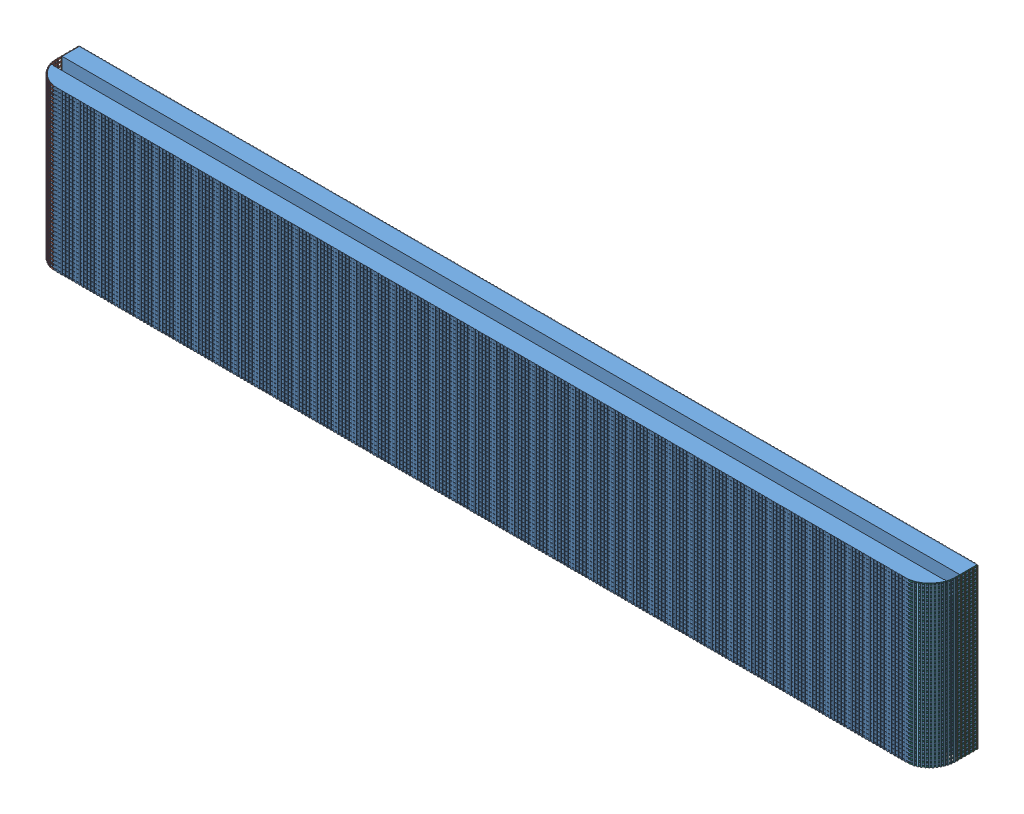
SolidWorks assembly B_neo_texture_part1, configuration Default. Lengths in mm.
Overall size (450.81 79.89 24).
123 component instances, 6 part files, 20 mates.
Components (placement in the parent):
- B_neo_part1-1: B_neo_part1 [Default] at (-250.0255 -30.6599 18.4974) size (450 79.89 24)
- Part5^B_neo_texture_part1-1: Part5^B_neo_texture_part1 [Default] at (-250.0255 49.2301 18.4974) x (1 0 0) z (0 1 0) size (10.93 23.6 0.6) (virtual)
- Part5^B_neo_texture_part1-2: Part5^B_neo_texture_part1 [Default] at (-250.0255 47.4301 18.4974) x (1 0 0) z (0 1 0) size (10.93 23.6 0.6) (virtual)
- Part5^B_neo_texture_part1-3: Part5^B_neo_texture_part1 [Default] at (-250.0255 45.6301 18.4974) x (1 0 0) z (0 1 0) size (10.93 23.6 0.6) (virtual)
- Part5^B_neo_texture_part1-4: Part5^B_neo_texture_part1 [Default] at (-250.0255 43.8301 18.4974) x (1 0 0) z (0 1 0) size (10.93 23.6 0.6) (virtual)
- Part5^B_neo_texture_part1-5: Part5^B_neo_texture_part1 [Default] at (-250.0255 42.0301 18.4974) x (1 0 0) z (0 1 0) size (10.93 23.6 0.6) (virtual)
- Part5^B_neo_texture_part1-6: Part5^B_neo_texture_part1 [Default] at (-250.0255 40.2301 18.4974) x (1 0 0) z (0 1 0) size (10.93 23.6 0.6) (virtual)
- Part5^B_neo_texture_part1-7: Part5^B_neo_texture_part1 [Default] at (-250.0255 38.4301 18.4974) x (1 0 0) z (0 1 0) size (10.93 23.6 0.6) (virtual)
- Part5^B_neo_texture_part1-8: Part5^B_neo_texture_part1 [Default] at (-250.0255 36.6301 18.4974) x (1 0 0) z (0 1 0) size (10.93 23.6 0.6) (virtual)
- Part5^B_neo_texture_part1-9: Part5^B_neo_texture_part1 [Default] at (-250.0255 34.8301 18.4974) x (1 0 0) z (0 1 0) size (10.93 23.6 0.6) (virtual)
- Part5^B_neo_texture_part1-10: Part5^B_neo_texture_part1 [Default] at (-250.0255 33.0301 18.4974) x (1 0 0) z (0 1 0) size (10.93 23.6 0.6) (virtual)
- Part5^B_neo_texture_part1-11: Part5^B_neo_texture_part1 [Default] at (-250.0255 31.2301 18.4974) x (1 0 0) z (0 1 0) size (10.93 23.6 0.6) (virtual)
- Part5^B_neo_texture_part1-12: Part5^B_neo_texture_part1 [Default] at (-250.0255 29.4301 18.4974) x (1 0 0) z (0 1 0) size (10.93 23.6 0.6) (virtual)
- Part5^B_neo_texture_part1-13: Part5^B_neo_texture_part1 [Default] at (-250.0255 27.6301 18.4974) x (1 0 0) z (0 1 0) size (10.93 23.6 0.6) (virtual)
- Part5^B_neo_texture_part1-14: Part5^B_neo_texture_part1 [Default] at (-250.0255 25.8301 18.4974) x (1 0 0) z (0 1 0) size (10.93 23.6 0.6) (virtual)
- Part5^B_neo_texture_part1-15: Part5^B_neo_texture_part1 [Default] at (-250.0255 24.0301 18.4974) x (1 0 0) z (0 1 0) size (10.93 23.6 0.6) (virtual)
- Part5^B_neo_texture_part1-16: Part5^B_neo_texture_part1 [Default] at (-250.0255 22.2301 18.4974) x (1 0 0) z (0 1 0) size (10.93 23.6 0.6) (virtual)
- Part5^B_neo_texture_part1-17: Part5^B_neo_texture_part1 [Default] at (-250.0255 20.4301 18.4974) x (1 0 0) z (0 1 0) size (10.93 23.6 0.6) (virtual)
- Part5^B_neo_texture_part1-18: Part5^B_neo_texture_part1 [Default] at (-250.0255 18.6301 18.4974) x (1 0 0) z (0 1 0) size (10.93 23.6 0.6) (virtual)
- Part5^B_neo_texture_part1-19: Part5^B_neo_texture_part1 [Default] at (-250.0255 16.8301 18.4974) x (1 0 0) z (0 1 0) size (10.93 23.6 0.6) (virtual)
- Part5^B_neo_texture_part1-20: Part5^B_neo_texture_part1 [Default] at (-250.0255 15.0301 18.4974) x (1 0 0) z (0 1 0) size (10.93 23.6 0.6) (virtual)
- Part5^B_neo_texture_part1-21: Part5^B_neo_texture_part1 [Default] at (-250.0255 13.2301 18.4974) x (1 0 0) z (0 1 0) size (10.93 23.6 0.6) (virtual)
- Part5^B_neo_texture_part1-22: Part5^B_neo_texture_part1 [Default] at (-250.0255 11.4301 18.4974) x (1 0 0) z (0 1 0) size (10.93 23.6 0.6) (virtual)
- Part5^B_neo_texture_part1-23: Part5^B_neo_texture_part1 [Default] at (-250.0255 9.6301 18.4974) x (1 0 0) z (0 1 0) size (10.93 23.6 0.6) (virtual)
- Part5^B_neo_texture_part1-24: Part5^B_neo_texture_part1 [Default] at (-250.0255 7.8301 18.4974) x (1 0 0) z (0 1 0) size (10.93 23.6 0.6) (virtual)
- Part5^B_neo_texture_part1-25: Part5^B_neo_texture_part1 [Default] at (-250.0255 6.0301 18.4974) x (1 0 0) z (0 1 0) size (10.93 23.6 0.6) (virtual)
- Part5^B_neo_texture_part1-26: Part5^B_neo_texture_part1 [Default] at (-250.0255 4.2301 18.4974) x (1 0 0) z (0 1 0) size (10.93 23.6 0.6) (virtual)
- Part5^B_neo_texture_part1-27: Part5^B_neo_texture_part1 [Default] at (-250.0255 2.4301 18.4974) x (1 0 0) z (0 1 0) size (10.93 23.6 0.6) (virtual)
- Part5^B_neo_texture_part1-28: Part5^B_neo_texture_part1 [Default] at (-250.0255 0.6301 18.4974) x (1 0 0) z (0 1 0) size (10.93 23.6 0.6) (virtual)
- Part5^B_neo_texture_part1-29: Part5^B_neo_texture_part1 [Default] at (-250.0255 -1.1699 18.4974) x (1 0 0) z (0 1 0) size (10.93 23.6 0.6) (virtual)
- Part5^B_neo_texture_part1-30: Part5^B_neo_texture_part1 [Default] at (-250.0255 -2.9699 18.4974) x (1 0 0) z (0 1 0) size (10.93 23.6 0.6) (virtual)
- Part5^B_neo_texture_part1-31: Part5^B_neo_texture_part1 [Default] at (-250.0255 -4.7699 18.4974) x (1 0 0) z (0 1 0) size (10.93 23.6 0.6) (virtual)
- Part5^B_neo_texture_part1-32: Part5^B_neo_texture_part1 [Default] at (-250.0255 -6.5699 18.4974) x (1 0 0) z (0 1 0) size (10.93 23.6 0.6) (virtual)
- Part5^B_neo_texture_part1-33: Part5^B_neo_texture_part1 [Default] at (-250.0255 -8.3699 18.4974) x (1 0 0) z (0 1 0) size (10.93 23.6 0.6) (virtual)
- Part5^B_neo_texture_part1-34: Part5^B_neo_texture_part1 [Default] at (-250.0255 -10.1699 18.4974) x (1 0 0) z (0 1 0) size (10.93 23.6 0.6) (virtual)
- Part5^B_neo_texture_part1-35: Part5^B_neo_texture_part1 [Default] at (-250.0255 -11.9699 18.4974) x (1 0 0) z (0 1 0) size (10.93 23.6 0.6) (virtual)
- Part5^B_neo_texture_part1-36: Part5^B_neo_texture_part1 [Default] at (-250.0255 -13.7699 18.4974) x (1 0 0) z (0 1 0) size (10.93 23.6 0.6) (virtual)
- Part5^B_neo_texture_part1-37: Part5^B_neo_texture_part1 [Default] at (-250.0255 -15.5699 18.4974) x (1 0 0) z (0 1 0) size (10.93 23.6 0.6) (virtual)
- Part5^B_neo_texture_part1-38: Part5^B_neo_texture_part1 [Default] at (-250.0255 -17.3699 18.4974) x (1 0 0) z (0 1 0) size (10.93 23.6 0.6) (virtual)
- Part5^B_neo_texture_part1-39: Part5^B_neo_texture_part1 [Default] at (-250.0255 -19.1699 18.4974) x (1 0 0) z (0 1 0) size (10.93 23.6 0.6) (virtual)
- Part5^B_neo_texture_part1-40: Part5^B_neo_texture_part1 [Default] at (-250.0255 -20.9699 18.4974) x (1 0 0) z (0 1 0) size (10.93 23.6 0.6) (virtual)
- Part5^B_neo_texture_part1-41: Part5^B_neo_texture_part1 [Default] at (-250.0255 -22.7699 18.4974) x (1 0 0) z (0 1 0) size (10.93 23.6 0.6) (virtual)
- Part5^B_neo_texture_part1-42: Part5^B_neo_texture_part1 [Default] at (-250.0255 -24.5699 18.4974) x (1 0 0) z (0 1 0) size (10.93 23.6 0.6) (virtual)
- Part5^B_neo_texture_part1-43: Part5^B_neo_texture_part1 [Default] at (-250.0255 -26.3699 18.4974) x (1 0 0) z (0 1 0) size (10.93 23.6 0.6) (virtual)
- Part5^B_neo_texture_part1-44: Part5^B_neo_texture_part1 [Default] at (-250.0255 -28.1699 18.4974) x (1 0 0) z (0 1 0) size (10.93 23.6 0.6) (virtual)
- Part5^B_neo_texture_part1-45: Part5^B_neo_texture_part1 [Default] at (-250.0255 -29.9699 18.4974) x (1 0 0) z (0 1 0) size (10.93 23.6 0.6) (virtual)
- Part6^B_neo_texture_part1-1: Part6^B_neo_texture_part1 [Default] at (-250.0255 49.2301 18.4974) x (1 0 0) z (0 1 0) size (450.8 0.81 79.89) (virtual)
- Part6^B_neo_texture_part1-2: Part6^B_neo_texture_part1 [Default] at (-250.0255 49.2301 20.4974) x (1 0 0) z (0 1 0) size (450.8 0.81 79.89) (virtual)
- Part6^B_neo_texture_part1-3: Part6^B_neo_texture_part1 [Default] at (-250.0255 49.2301 22.4974) x (1 0 0) z (0 1 0) size (450.8 0.81 79.89) (virtual)
- Part6^B_neo_texture_part1-4: Part6^B_neo_texture_part1 [Default] at (-250.0255 49.2301 24.4974) x (1 0 0) z (0 1 0) size (450.8 0.81 79.89) (virtual)
- Part6^B_neo_texture_part1-5: Part6^B_neo_texture_part1 [Default] at (-250.0255 49.2301 26.4974) x (1 0 0) z (0 1 0) size (450.8 0.81 79.89) (virtual)
- Part6^B_neo_texture_part1-6: Part6^B_neo_texture_part1 [Default] at (-250.0255 49.2301 28.4974) x (1 0 0) z (0 1 0) size (450.8 0.81 79.89) (virtual)
- Part7^B_neo_texture_part1-1: Part7^B_neo_texture_part1 [Default] at (-250.0255 49.2301 28.4974) x (1 0 0) z (0 1 0) size (0.2 0.6 79.89) (virtual)
- Part7^B_neo_texture_part1-2: Part7^B_neo_texture_part1 [Default] at (-247.592 49.2301 29.7325) x (0.994522 0 -0.104528) z (0 1 0) size (0.2 0.6 79.89) (virtual)
- Part7^B_neo_texture_part1-3: Part7^B_neo_texture_part1 [Default] at (-245.0427 49.2301 30.7064) x (0.978148 0 -0.207912) z (0 1 0) size (0.2 0.6 79.89) (virtual)
- Part7^B_neo_texture_part1-4: Part7^B_neo_texture_part1 [Default] at (-242.4055 49.2301 31.4085) x (0.951057 0 -0.309017) z (0 1 0) size (0.2 0.6 79.89) (virtual)
- Part7^B_neo_texture_part1-5: Part7^B_neo_texture_part1 [Default] at (-239.7094 49.2301 31.8312) x (0.913545 0 -0.406737) z (0 1 0) size (0.2 0.6 79.89) (virtual)
- Part7^B_neo_texture_part1-6: Part7^B_neo_texture_part1 [Default] at (-236.9839 49.2301 31.9696) x (0.866025 0 -0.5) z (0 1 0) size (0.2 0.6 79.89) (virtual)
- Part7^B_neo_texture_part1-7: Part7^B_neo_texture_part1 [Default] at (-234.2588 49.2301 31.8224) x (0.809017 0 -0.587785) z (0 1 0) size (0.2 0.6 79.89) (virtual)
- Part7^B_neo_texture_part1-8: Part7^B_neo_texture_part1 [Default] at (-231.5641 49.2301 31.3912) x (0.743145 0 -0.669131) z (0 1 0) size (0.2 0.6 79.89) (virtual)
- Part7^B_neo_texture_part1-9: Part7^B_neo_texture_part1 [Default] at (-228.9292 49.2301 30.6807) x (0.669131 0 -0.743145) z (0 1 0) size (0.2 0.6 79.89) (virtual)
- Part7^B_neo_texture_part1-10: Part7^B_neo_texture_part1 [Default] at (-226.383 49.2301 29.6986) x (0.587785 0 -0.809017) z (0 1 0) size (0.2 0.6 79.89) (virtual)
- Part7^B_neo_texture_part1-11: Part7^B_neo_texture_part1 [Default] at (-223.9534 49.2301 28.4558) x (0.5 0 -0.866025) z (0 1 0) size (0.2 0.6 79.89) (virtual)
- Part7^B_neo_texture_part1-12: Part7^B_neo_texture_part1 [Default] at (-221.667 49.2301 26.9658) x (0.406737 0 -0.913545) z (0 1 0) size (0.2 0.6 79.89) (virtual)
- Part7^B_neo_texture_part1-13: Part7^B_neo_texture_part1 [Default] at (-219.5489 49.2301 25.245) x (0.309017 0 -0.951057) z (0 1 0) size (0.2 0.6 79.89) (virtual)
- Part8^B_neo_texture_part1-1: Part8^B_neo_texture_part1 [Default] at (-250.0255 49.2301 28.4974) x (1 0 0) z (0 1 0) size (0.2 0.6 79.89) (virtual)
- Part8^B_neo_texture_part1-2: Part8^B_neo_texture_part1 [Default] at (-249.9939 49.2301 -17.3053) x (0.994522 0 0.104528) z (0 1 0) size (0.2 0.6 79.89) (virtual)
- Part8^B_neo_texture_part1-3: Part8^B_neo_texture_part1 [Default] at (-245.1748 49.2301 -62.8538) x (0.978148 0 0.207912) z (0 1 0) size (0.2 0.6 79.89) (virtual)
- Part8^B_neo_texture_part1-4: Part8^B_neo_texture_part1 [Default] at (-235.621 49.2301 -107.6491) x (0.951057 0 0.309017) z (0 1 0) size (0.2 0.6 79.89) (virtual)
- Part8^B_neo_texture_part1-5: Part8^B_neo_texture_part1 [Default] at (-221.4372 49.2301 -151.2003) x (0.913545 0 0.406737) z (0 1 0) size (0.2 0.6 79.89) (virtual)
- Part8^B_neo_texture_part1-6: Part8^B_neo_texture_part1 [Default] at (-202.7786 49.2301 -193.0304) x (0.866025 0 0.5) z (0 1 0) size (0.2 0.6 79.89) (virtual)
- Part8^B_neo_texture_part1-7: Part8^B_neo_texture_part1 [Default] at (-179.8499 49.2301 -232.6809) x (0.809017 0 0.587785) z (0 1 0) size (0.2 0.6 79.89) (virtual)
- Part8^B_neo_texture_part1-8: Part8^B_neo_texture_part1 [Default] at (-152.9022 49.2301 -269.7176) x (0.743145 0 0.669131) z (0 1 0) size (0.2 0.6 79.89) (virtual)
- Part8^B_neo_texture_part1-9: Part8^B_neo_texture_part1 [Default] at (-122.2307 49.2301 -303.7345) x (0.669131 0 0.743145) z (0 1 0) size (0.2 0.6 79.89) (virtual)
- Part8^B_neo_texture_part1-10: Part8^B_neo_texture_part1 [Default] at (-88.1715 49.2301 -334.359) x (0.587785 0 0.809017) z (0 1 0) size (0.2 0.6 79.89) (virtual)
- Part8^B_neo_texture_part1-11: Part8^B_neo_texture_part1 [Default] at (-51.0977 49.2301 -361.2557) x (0.5 0 0.866025) z (0 1 0) size (0.2 0.6 79.89) (virtual)
- Part8^B_neo_texture_part1-12: Part8^B_neo_texture_part1 [Default] at (-11.4156 49.2301 -384.1297) x (0.406737 0 0.913545) z (0 1 0) size (0.2 0.6 79.89) (virtual)
- Part8^B_neo_texture_part1-13: Part8^B_neo_texture_part1 [Default] at (30.4402 49.2301 -402.7305) x (0.309017 0 0.951057) z (0 1 0) size (0.2 0.6 79.89) (virtual)
- Part10^B_neo_texture_part1-1: Part10^B_neo_texture_part1 [Default] at (-250.0255 49.2301 18.4974) x (1 0 0) z (0 1 0) size (10.93 23.6 0.6) (virtual)
- Part10^B_neo_texture_part1-2: Part10^B_neo_texture_part1 [Default] at (-250.0255 47.4301 18.4974) x (1 0 0) z (0 1 0) size (10.93 23.6 0.6) (virtual)
- Part10^B_neo_texture_part1-3: Part10^B_neo_texture_part1 [Default] at (-250.0255 45.6301 18.4974) x (1 0 0) z (0 1 0) size (10.93 23.6 0.6) (virtual)
- Part10^B_neo_texture_part1-4: Part10^B_neo_texture_part1 [Default] at (-250.0255 43.8301 18.4974) x (1 0 0) z (0 1 0) size (10.93 23.6 0.6) (virtual)
- Part10^B_neo_texture_part1-5: Part10^B_neo_texture_part1 [Default] at (-250.0255 42.0301 18.4974) x (1 0 0) z (0 1 0) size (10.93 23.6 0.6) (virtual)
- Part10^B_neo_texture_part1-6: Part10^B_neo_texture_part1 [Default] at (-250.0255 40.2301 18.4974) x (1 0 0) z (0 1 0) size (10.93 23.6 0.6) (virtual)
- Part10^B_neo_texture_part1-7: Part10^B_neo_texture_part1 [Default] at (-250.0255 38.4301 18.4974) x (1 0 0) z (0 1 0) size (10.93 23.6 0.6) (virtual)
- Part10^B_neo_texture_part1-8: Part10^B_neo_texture_part1 [Default] at (-250.0255 36.6301 18.4974) x (1 0 0) z (0 1 0) size (10.93 23.6 0.6) (virtual)
- Part10^B_neo_texture_part1-9: Part10^B_neo_texture_part1 [Default] at (-250.0255 34.8301 18.4974) x (1 0 0) z (0 1 0) size (10.93 23.6 0.6) (virtual)
- Part10^B_neo_texture_part1-10: Part10^B_neo_texture_part1 [Default] at (-250.0255 33.0301 18.4974) x (1 0 0) z (0 1 0) size (10.93 23.6 0.6) (virtual)
- Part10^B_neo_texture_part1-11: Part10^B_neo_texture_part1 [Default] at (-250.0255 31.2301 18.4974) x (1 0 0) z (0 1 0) size (10.93 23.6 0.6) (virtual)
- Part10^B_neo_texture_part1-12: Part10^B_neo_texture_part1 [Default] at (-250.0255 29.4301 18.4974) x (1 0 0) z (0 1 0) size (10.93 23.6 0.6) (virtual)
- Part10^B_neo_texture_part1-13: Part10^B_neo_texture_part1 [Default] at (-250.0255 27.6301 18.4974) x (1 0 0) z (0 1 0) size (10.93 23.6 0.6) (virtual)
- Part10^B_neo_texture_part1-14: Part10^B_neo_texture_part1 [Default] at (-250.0255 25.8301 18.4974) x (1 0 0) z (0 1 0) size (10.93 23.6 0.6) (virtual)
- Part10^B_neo_texture_part1-15: Part10^B_neo_texture_part1 [Default] at (-250.0255 24.0301 18.4974) x (1 0 0) z (0 1 0) size (10.93 23.6 0.6) (virtual)
- Part10^B_neo_texture_part1-16: Part10^B_neo_texture_part1 [Default] at (-250.0255 22.2301 18.4974) x (1 0 0) z (0 1 0) size (10.93 23.6 0.6) (virtual)
- Part10^B_neo_texture_part1-17: Part10^B_neo_texture_part1 [Default] at (-250.0255 20.4301 18.4974) x (1 0 0) z (0 1 0) size (10.93 23.6 0.6) (virtual)
- Part10^B_neo_texture_part1-18: Part10^B_neo_texture_part1 [Default] at (-250.0255 18.6301 18.4974) x (1 0 0) z (0 1 0) size (10.93 23.6 0.6) (virtual)
- Part10^B_neo_texture_part1-19: Part10^B_neo_texture_part1 [Default] at (-250.0255 16.8301 18.4974) x (1 0 0) z (0 1 0) size (10.93 23.6 0.6) (virtual)
- Part10^B_neo_texture_part1-20: Part10^B_neo_texture_part1 [Default] at (-250.0255 15.0301 18.4974) x (1 0 0) z (0 1 0) size (10.93 23.6 0.6) (virtual)
- Part10^B_neo_texture_part1-21: Part10^B_neo_texture_part1 [Default] at (-250.0255 13.2301 18.4974) x (1 0 0) z (0 1 0) size (10.93 23.6 0.6) (virtual)
- Part10^B_neo_texture_part1-22: Part10^B_neo_texture_part1 [Default] at (-250.0255 11.4301 18.4974) x (1 0 0) z (0 1 0) size (10.93 23.6 0.6) (virtual)
- Part10^B_neo_texture_part1-23: Part10^B_neo_texture_part1 [Default] at (-250.0255 9.6301 18.4974) x (1 0 0) z (0 1 0) size (10.93 23.6 0.6) (virtual)
- Part10^B_neo_texture_part1-24: Part10^B_neo_texture_part1 [Default] at (-250.0255 7.8301 18.4974) x (1 0 0) z (0 1 0) size (10.93 23.6 0.6) (virtual)
- Part10^B_neo_texture_part1-25: Part10^B_neo_texture_part1 [Default] at (-250.0255 6.0301 18.4974) x (1 0 0) z (0 1 0) size (10.93 23.6 0.6) (virtual)
- Part10^B_neo_texture_part1-26: Part10^B_neo_texture_part1 [Default] at (-250.0255 4.2301 18.4974) x (1 0 0) z (0 1 0) size (10.93 23.6 0.6) (virtual)
- Part10^B_neo_texture_part1-27: Part10^B_neo_texture_part1 [Default] at (-250.0255 2.4301 18.4974) x (1 0 0) z (0 1 0) size (10.93 23.6 0.6) (virtual)
- Part10^B_neo_texture_part1-28: Part10^B_neo_texture_part1 [Default] at (-250.0255 0.6301 18.4974) x (1 0 0) z (0 1 0) size (10.93 23.6 0.6) (virtual)
- Part10^B_neo_texture_part1-29: Part10^B_neo_texture_part1 [Default] at (-250.0255 -1.1699 18.4974) x (1 0 0) z (0 1 0) size (10.93 23.6 0.6) (virtual)
- Part10^B_neo_texture_part1-30: Part10^B_neo_texture_part1 [Default] at (-250.0255 -2.9699 18.4974) x (1 0 0) z (0 1 0) size (10.93 23.6 0.6) (virtual)
- Part10^B_neo_texture_part1-31: Part10^B_neo_texture_part1 [Default] at (-250.0255 -4.7699 18.4974) x (1 0 0) z (0 1 0) size (10.93 23.6 0.6) (virtual)
- Part10^B_neo_texture_part1-32: Part10^B_neo_texture_part1 [Default] at (-250.0255 -6.5699 18.4974) x (1 0 0) z (0 1 0) size (10.93 23.6 0.6) (virtual)
- Part10^B_neo_texture_part1-33: Part10^B_neo_texture_part1 [Default] at (-250.0255 -8.3699 18.4974) x (1 0 0) z (0 1 0) size (10.93 23.6 0.6) (virtual)
- Part10^B_neo_texture_part1-34: Part10^B_neo_texture_part1 [Default] at (-250.0255 -10.1699 18.4974) x (1 0 0) z (0 1 0) size (10.93 23.6 0.6) (virtual)
- Part10^B_neo_texture_part1-35: Part10^B_neo_texture_part1 [Default] at (-250.0255 -11.9699 18.4974) x (1 0 0) z (0 1 0) size (10.93 23.6 0.6) (virtual)
- Part10^B_neo_texture_part1-36: Part10^B_neo_texture_part1 [Default] at (-250.0255 -13.7699 18.4974) x (1 0 0) z (0 1 0) size (10.93 23.6 0.6) (virtual)
- Part10^B_neo_texture_part1-37: Part10^B_neo_texture_part1 [Default] at (-250.0255 -15.5699 18.4974) x (1 0 0) z (0 1 0) size (10.93 23.6 0.6) (virtual)
- Part10^B_neo_texture_part1-38: Part10^B_neo_texture_part1 [Default] at (-250.0255 -17.3699 18.4974) x (1 0 0) z (0 1 0) size (10.93 23.6 0.6) (virtual)
- Part10^B_neo_texture_part1-39: Part10^B_neo_texture_part1 [Default] at (-250.0255 -19.1699 18.4974) x (1 0 0) z (0 1 0) size (10.93 23.6 0.6) (virtual)
- Part10^B_neo_texture_part1-40: Part10^B_neo_texture_part1 [Default] at (-250.0255 -20.9699 18.4974) x (1 0 0) z (0 1 0) size (10.93 23.6 0.6) (virtual)
- Part10^B_neo_texture_part1-41: Part10^B_neo_texture_part1 [Default] at (-250.0255 -22.7699 18.4974) x (1 0 0) z (0 1 0) size (10.93 23.6 0.6) (virtual)
- Part10^B_neo_texture_part1-42: Part10^B_neo_texture_part1 [Default] at (-250.0255 -24.5699 18.4974) x (1 0 0) z (0 1 0) size (10.93 23.6 0.6) (virtual)
- Part10^B_neo_texture_part1-43: Part10^B_neo_texture_part1 [Default] at (-250.0255 -26.3699 18.4974) x (1 0 0) z (0 1 0) size (10.93 23.6 0.6) (virtual)
- Part10^B_neo_texture_part1-44: Part10^B_neo_texture_part1 [Default] at (-250.0255 -28.1699 18.4974) x (1 0 0) z (0 1 0) size (10.93 23.6 0.6) (virtual)
- Part10^B_neo_texture_part1-45: Part10^B_neo_texture_part1 [Default] at (-250.0255 -29.9699 18.4974) x (1 0 0) z (0 1 0) size (10.93 23.6 0.6) (virtual)
Mates (geometry in assembly coordinates):
- InPlace1: in place: plane of B_neo_part1-1 through (199.9745 49.2301 3.7974) normal (0 1 0); plane of ? through (0 49.2301 0) normal (0 1 0); moOrthogonalPlaneRef_w of B_neo_part1-1 through (199.9745 49.2301 3.7974) normal (0 1 0); plane of ? through (0 49.2301 0) normal (0 0 -1); plane of B_neo_part1-1 through (199.9745 49.2301 3.7974) normal (0 1 0); plane of ? through (0 49.2301 0) normal (1 0 0); plane of B_neo_part1-1 through (199.9745 49.2301 3.7974) normal (0 1 0); unknown of ?
- Coincident1: coincident aligned: plane of ?; plane of ?
- Coincident2: coincident aligned: moOrthogonalPlaneRef_w of B_neo_part1-1 through (-250.0255 49.2301 18.4974) normal (0 0 -1); plane of Part5^B_neo_texture_part1-1 through (-250.0255 49.2301 18.4974) normal (0 0 -1)
- Coincident3: coincident anti-aligned: moOrthogonalPlaneRef_w of B_neo_part1-1 through (-250.0255 49.2301 18.4974) normal (-1 0 0); plane of Part5^B_neo_texture_part1-1 through (-250.0255 49.2301 18.4974) normal (1 0 0)
- InPlace2: in place: plane of ? through (-237.0255 49.2301 5.8974) normal (0 1 0); plane of ? through (0 49.2301 0) normal (0 1 0); plane of ? through (-237.0255 49.2301 5.8974) normal (0 1 0); plane of ? through (0 49.2301 0) normal (0 0 -1); plane of ? through (-237.0255 49.2301 5.8974) normal (0 1 0); plane of ? through (0 49.2301 0) normal (1 0 0); plane of ? through (-237.0255 49.2301 5.8974) normal (0 1 0); unknown of ?
- Coincident4: coincident aligned: plane of ?; plane of ?
- Coincident5: coincident aligned: moOrthogonalPlaneRef_w of Part5^B_neo_texture_part1-1 through (-250.0255 49.2301 18.4974) normal (0 0 -1); plane of Part6^B_neo_texture-1 through (-250.0255 49.2301 18.4974) normal (0 0 -1)
- Coincident6: coincident anti-aligned: moOrthogonalPlaneRef_w of Part5^B_neo_texture_part1-1 through (-250.0255 49.2301 18.4974) normal (-1 0 0); plane of Part6^B_neo_texture-1 through (-250.0255 49.2301 18.4974) normal (1 0 0)
- InPlace3: in place: plane of ? through (-250.0255 49.2301 28.4974) normal (0 1 0); plane of ? through (0 49.2301 0) normal (0 1 0); plane of ? through (-250.0255 49.2301 28.4974) normal (0 1 0); plane of ? through (0 49.2301 0) normal (0 0 -1); plane of ? through (-250.0255 49.2301 28.4974) normal (0 1 0); plane of ? through (0 49.2301 0) normal (1 0 0); plane of ? through (-250.0255 49.2301 28.4974) normal (0 1 0); unknown of ?
- Coincident7: coincident aligned: plane of ?; plane of ?
- Coincident8: coincident aligned: moOrthogonalPlaneRef_w of Part6^B_neo_texture-6 through (-250.0255 49.2301 28.4974) normal (0 0 -1); plane of Part7^B_neo_texture-1 through (-250.0255 49.2301 28.4974) normal (0 0 -1)
- Coincident9: coincident anti-aligned: moOrthogonalPlaneRef_w of Part6^B_neo_texture-6 through (-250.0255 49.2301 28.4974) normal (-1 0 0); plane of Part7^B_neo_texture-1 through (-250.0255 49.2301 28.4974) normal (1 0 0)
- InPlace4: in place: plane of ? through (-250.0255 49.2301 28.4974) normal (0 1 0); plane of ? through (0 49.2301 0) normal (0 1 0); plane of ? through (-250.0255 49.2301 28.4974) normal (0 1 0); plane of ? through (0 49.2301 0) normal (0 0 -1); plane of ? through (-250.0255 49.2301 28.4974) normal (0 1 0); plane of ? through (0 49.2301 0) normal (1 0 0); plane of ? through (-250.0255 49.2301 28.4974) normal (0 1 0); unknown of ?
- Coincident10: coincident aligned: plane of ?; plane of ?
- Coincident11: coincident aligned: moOrthogonalPlaneRef_w of Part6^B_neo_texture-6 through (-250.0255 49.2301 28.4974) normal (0 0 -1); plane of Part8^B_neo_texture-1 through (-250.0255 49.2301 28.4974) normal (0 0 -1)
- Coincident12: coincident anti-aligned: moOrthogonalPlaneRef_w of Part6^B_neo_texture-6 through (-250.0255 49.2301 28.4974) normal (-1 0 0); plane of Part8^B_neo_texture-1 through (-250.0255 49.2301 28.4974) normal (1 0 0)
- InPlace5: in place: plane of B_neo_part1-1 through (199.9745 49.2301 3.7974) normal (0 1 0); plane of ? through (0 49.2301 0) normal (0 1 0); plane of B_neo_part1-1 through (199.9745 49.2301 3.7974) normal (0 1 0); plane of ? through (0 49.2301 0) normal (0 0 -1); plane of B_neo_part1-1 through (199.9745 49.2301 3.7974) normal (0 1 0); plane of ? through (0 49.2301 0) normal (1 0 0); plane of B_neo_part1-1 through (199.9745 49.2301 3.7974) normal (0 1 0); unknown of ?
- Coincident1: coincident aligned: plane of ?; plane of ?
- Coincident2: coincident aligned: moOrthogonalPlaneRef_w of B_neo_part1-1 through (-250.0255 49.2301 18.4974) normal (0 0 -1); plane of Part10^B_neo_texture_part1-1 through (-250.0255 49.2301 18.4974) normal (0 0 -1)
- Coincident3: coincident anti-aligned: moOrthogonalPlaneRef_w of B_neo_part1-1 through (-250.0255 49.2301 18.4974) normal (-1 0 0); plane of Part10^B_neo_texture_part1-1 through (-250.0255 49.2301 18.4974) normal (1 0 0)
